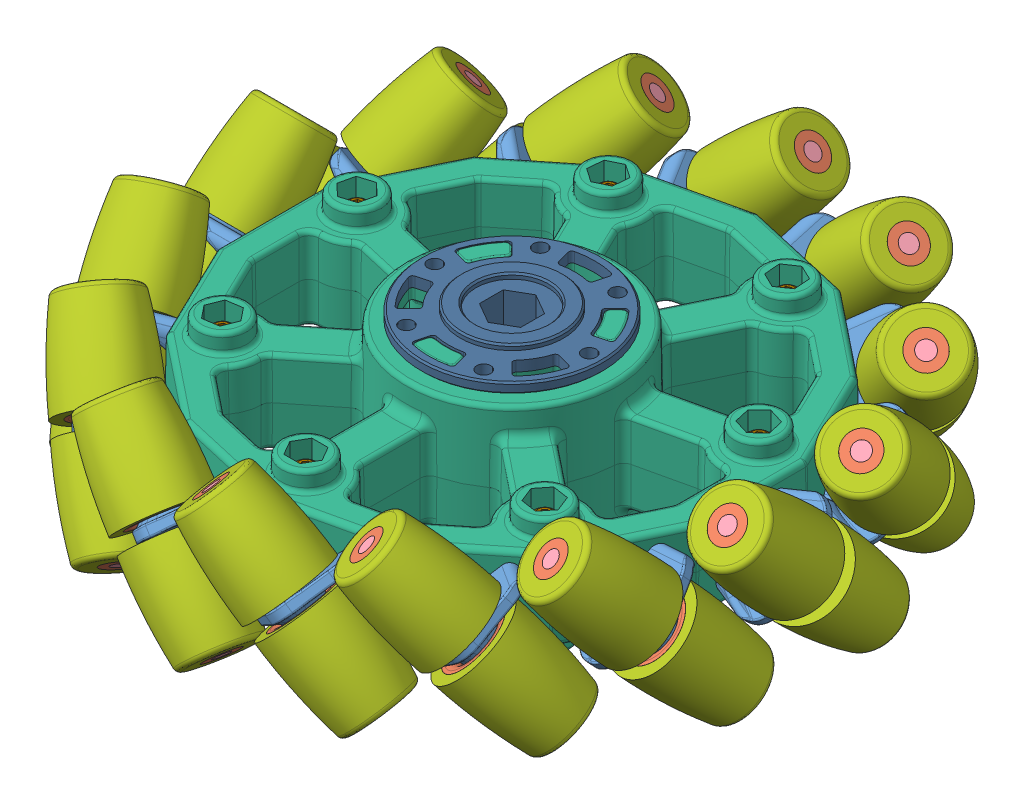
SolidWorks assembly 8in mecanum right vex 217-2587, configuration Default. Lengths in mm.
Overall size (213.38 69.6 218.31).
136 component instances, 11 part files, 6 mates.
Components (placement in the parent):
- 217-2586-002 Rev2-1: 217-2586-002 Rev2 [Default] at (67.5204 0.2406 0.0923) x (0 0 -1) z (1 0 0) size (26.84 25.28 30.09)
- 217-2586-003 Rev2-1: 217-2586-003 Rev2 [Default] at (88.2976 4.2468 4.0985) x (-0.854327 -0.367509 0.367509) z (-0.519737 0.6041 -0.6041) size (19.46 28.57 19.46)
- 217-2586-003 Rev2-2: 217-2586-003 Rev2 [Default] at (88.2976 -3.7657 -3.9139) x (0.717269 -0.492709 0.492709) z (0.696796 0.507186 -0.507186) size (19.46 28.57 19.46)
- 217-2586-005 Rev2-1: 217-2586-005 Rev2 [Default] at (88.2976 6.5692 6.4209) x (0 -0.707107 -0.707107) z (0.707107 -0.5 0.5) size (8.5 8 8)
- 217-2586-005 Rev2-2: 217-2586-005 Rev2 [Default] at (88.2976 -6.088 -6.2363) x (0 -0.707107 -0.707107) z (0.707107 -0.5 0.5) size (8.5 8 8)
- 217-2586-007 Rev1-1: 217-2586-007 Rev1 [Default] at (88.2976 0.2406 0.0923) x (0 -0.707107 -0.707107) z (0.543569 -0.59352 0.59352) size (61.72 5 5)
- 217-2586-008 Rev1-1: 217-2586-008 Rev1 [Default] at (-11.9459 2.5442 -20.6627) x (0.866025 0 -0.5) z (0 -1 0) size (7.33 6.35 31.75)
- 217-2587-001 Rev2-1: 217-2587-001 Rev2 [Default] at (-0.0396 6.3542 -0.0405) x (1 0 0) z (0 -1 0) size (148.4 151.99 28.55)
- 217-2587-001 Rev2-2: 217-2587-001 Rev2 [Default] at (-0.0396 -6.3458 -0.0405) x (-1 0 0) z (0 1 0) size (148.4 151.99 28.55)
- 217-2587-002 Rev2-1: 217-2587-002 Rev2 [Default] at (88.2976 0.6392 0.4909) x (0.779232 -0.443169 0.443169) z (0.626736 0.551 -0.551) size (26.1 28.57 26.1)
- 217-2587-002 Rev2-2: 217-2587-002 Rev2 [Default] at (88.2976 -0.158 -0.3063) x (0.779223 -0.443177 0.443177) z (-0.626747 -0.550994 0.550994) size (26.1 28.57 26.1)
- NUT-832-NYLOCK-1: NUT-832-NYLOCK [Default] at (-49.6859 -13.6521 39.5511) x (0.365341 0 -0.930874) z (-0.930874 0 -0.365341) size (10.2 5.86 8.12)
- SCREW-832-1250-1: SCREW-832-1250 [Default] at (-49.6859 14.914 39.5511) x (0 -1 0) z (0 0 1) size (33.96 7.92 7.92)
- 217-2586-008 Rev1-2: 217-2586-008 Rev1 [Default] at (11.8666 2.5442 -20.6627) x (0.866025 0 0.5) z (0 -1 0) size (7.33 6.35 31.75)
- 217-2586-008 Rev1-3: 217-2586-008 Rev1 [Default] at (23.7729 2.5442 -0.0405) x (0 0 1) z (0 -1 0) size (7.33 6.35 31.75)
- 217-2586-008 Rev1-4: 217-2586-008 Rev1 [Default] at (11.8666 2.5442 20.5817) x (-0.866025 0 0.5) z (0 -1 0) size (7.33 6.35 31.75)
- 217-2586-008 Rev1-5: 217-2586-008 Rev1 [Default] at (-11.9459 2.5442 20.5817) x (-0.866025 0 -0.5) z (0 -1 0) size (7.33 6.35 31.75)
- 217-2586-008 Rev1-6: 217-2586-008 Rev1 [Default] at (-23.8521 2.5442 -0.0405) x (0 0 -1) z (0 -1 0) size (7.33 6.35 31.75)
- NUT-832-NYLOCK-2: NUT-832-NYLOCK [Default] at (-0.0396 -13.6521 63.4595) x (-0.5 0 -0.866025) z (-0.866025 0 0.5) size (10.2 5.86 8.12)
- NUT-832-NYLOCK-3: NUT-832-NYLOCK [Default] at (49.6067 -13.6521 39.5511) x (-0.988831 0 -0.149042) z (-0.149042 0 0.988831) size (10.2 5.86 8.12)
- NUT-832-NYLOCK-4: NUT-832-NYLOCK [Default] at (61.8683 -13.6521 -14.1706) x (-0.733052 0 0.680173) z (0.680173 0 0.733052) size (10.2 5.86 8.12)
- NUT-832-NYLOCK-5: NUT-832-NYLOCK [Default] at (27.512 -13.6521 -57.252) x (0.07473 0 0.997204) z (0.997204 0 -0.07473) size (10.2 5.86 8.12)
- NUT-832-NYLOCK-6: NUT-832-NYLOCK [Default] at (-27.5912 -13.6521 -57.252) x (0.826239 0 0.56332) z (0.56332 0 -0.826239) size (10.2 5.86 8.12)
- NUT-832-NYLOCK-7: NUT-832-NYLOCK [Default] at (-61.9475 -13.6521 -14.1706) x (0.955573 0 -0.294755) z (-0.294755 0 -0.955573) size (10.2 5.86 8.12)
- SCREW-832-1250-2: SCREW-832-1250 [Default] at (-0.0396 14.914 63.4595) x (0 -1 0) z (0.781831 0 0.62349) size (33.96 7.92 7.92)
- SCREW-832-1250-3: SCREW-832-1250 [Default] at (49.6067 14.914 39.5511) x (0 -1 0) z (0.974928 0 -0.222521) size (33.96 7.92 7.92)
- SCREW-832-1250-4: SCREW-832-1250 [Default] at (61.8683 14.914 -14.1706) x (0 -1 0) z (0.433884 0 -0.900969) size (33.96 7.92 7.92)
- SCREW-832-1250-5: SCREW-832-1250 [Default] at (27.512 14.914 -57.252) x (0 -1 0) z (-0.433884 0 -0.900969) size (33.96 7.92 7.92)
- SCREW-832-1250-6: SCREW-832-1250 [Default] at (-27.5912 14.914 -57.252) x (0 -1 0) z (-0.974928 0 -0.222521) size (33.96 7.92 7.92)
- SCREW-832-1250-7: SCREW-832-1250 [Default] at (-61.9475 14.914 -14.1706) x (0 -1 0) z (-0.781831 0 0.62349) size (33.96 7.92 7.92)
- 217-2586-002 Rev2-2: 217-2586-002 Rev2 [Default] at (60.8875 0.2406 -29.234) x (-0.433884 0 -0.900969) z (0.900969 0 -0.433884) size (26.84 25.28 30.09)
- 217-2586-002 Rev2-3: 217-2586-002 Rev2 [Default] at (42.1872 0.2406 -52.7782) x (-0.781831 0 -0.62349) z (0.62349 0 -0.781831) size (26.84 25.28 30.09)
- 217-2586-002 Rev2-4: 217-2586-002 Rev2 [Default] at (15.1234 0.2406 -65.8771) x (-0.974928 0 -0.222521) z (0.222521 0 -0.974928) size (26.84 25.28 30.09)
- 217-2586-002 Rev2-5: 217-2586-002 Rev2 [Default] at (-14.9437 0.2406 -65.9362) x (-0.974928 0 0.222521) z (-0.222521 0 -0.974928) size (26.84 25.28 30.09)
- 217-2586-002 Rev2-6: 217-2586-002 Rev2 [Default] at (-42.0588 0.2406 -52.9438) x (-0.781831 0 0.62349) z (-0.62349 0 -0.781831) size (26.84 25.28 30.09)
- 217-2586-002 Rev2-7: 217-2586-002 Rev2 [Default] at (-60.8515 0.2406 -29.4733) x (-0.433884 0 0.900969) z (-0.900969 0 -0.433884) size (26.84 25.28 30.09)
- 217-2586-002 Rev2-8: 217-2586-002 Rev2 [Default] at (-67.5996 0.2406 -0.1733) x (0 0 1) z (-1 0 0) size (26.84 25.28 30.09)
- 217-2586-002 Rev2-9: 217-2586-002 Rev2 [Default] at (-60.9667 0.2406 29.1531) x (0.433884 0 0.900969) z (-0.900969 0 0.433884) size (26.84 25.28 30.09)
- 217-2586-002 Rev2-10: 217-2586-002 Rev2 [Default] at (-42.2664 0.2406 52.6973) x (0.781831 0 0.62349) z (-0.62349 0 0.781831) size (26.84 25.28 30.09)
- 217-2586-002 Rev2-11: 217-2586-002 Rev2 [Default] at (-15.2026 0.2406 65.7961) x (0.974928 0 0.222521) z (-0.222521 0 0.974928) size (26.84 25.28 30.09)
- 217-2586-002 Rev2-12: 217-2586-002 Rev2 [Default] at (14.8644 0.2406 65.8552) x (0.974928 0 -0.222521) z (0.222521 0 0.974928) size (26.84 25.28 30.09)
- 217-2586-002 Rev2-13: 217-2586-002 Rev2 [Default] at (41.9795 0.2406 52.8628) x (0.781831 0 -0.62349) z (0.62349 0 0.781831) size (26.84 25.28 30.09)
- 217-2586-002 Rev2-14: 217-2586-002 Rev2 [Default] at (60.7722 0.2406 29.3923) x (0.433884 0 -0.900969) z (0.900969 0 0.433884) size (26.84 25.28 30.09)
- 217-2586-003 Rev2-3: 217-2586-003 Rev2 [Default] at (81.3453 4.2468 -34.6394) x (-0.610265 -0.367509 0.701793) z (-0.730376 0.6041 -0.31877) size (19.46 28.57 19.46)
- 217-2586-003 Rev2-4: 217-2586-003 Rev2 [Default] at (58.2737 4.2468 -66.5247) x (-0.245334 -0.367509 0.897078) z (-0.796355 0.6041 0.029696) size (19.46 28.57 19.46)
- 217-2586-003 Rev2-5: 217-2586-003 Rev2 [Default] at (23.6525 4.2468 -85.2419) x (0.16819 -0.367509 0.914685) z (-0.704606 0.6041 0.372281) size (19.46 28.57 19.46)
- 217-2586-003 Rev2-6: 217-2586-003 Rev2 [Default] at (-15.6612 4.2468 -87.0839) x (0.548401 -0.367509 0.751128) z (-0.473302 0.6041 0.641131) size (19.46 28.57 19.46)
- 217-2586-003 Rev2-7: 217-2586-003 Rev2 [Default] at (-51.8809 4.2468 -71.6859) x (0.819994 -0.367509 0.438801) z (-0.148254 0.6041 0.782997) size (19.46 28.57 19.46)
- 217-2586-003 Rev2-8: 217-2586-003 Rev2 [Default] at (-77.8328 4.2468 -42.0977) x (0.929178 -0.367509 0.039564) z (0.206157 0.6041 0.769781) size (19.46 28.57 19.46)
- 217-2586-003 Rev2-9: 217-2586-003 Rev2 [Default] at (-88.3768 4.2468 -4.1795) x (0.854327 -0.367509 -0.367509) z (0.519737 0.6041 0.6041) size (19.46 28.57 19.46)
- 217-2586-003 Rev2-10: 217-2586-003 Rev2 [Default] at (-81.4245 4.2468 34.5585) x (0.610265 -0.367509 -0.701793) z (0.730376 0.6041 0.31877) size (19.46 28.57 19.46)
- 217-2586-003 Rev2-11: 217-2586-003 Rev2 [Default] at (-58.353 4.2468 66.4437) x (0.245334 -0.367509 -0.897078) z (0.796355 0.6041 -0.029696) size (19.46 28.57 19.46)
- 217-2586-003 Rev2-12: 217-2586-003 Rev2 [Default] at (-23.7317 4.2468 85.1609) x (-0.16819 -0.367509 -0.914685) z (0.704606 0.6041 -0.372281) size (19.46 28.57 19.46)
- 217-2586-003 Rev2-13: 217-2586-003 Rev2 [Default] at (15.582 4.2468 87.0029) x (-0.548401 -0.367509 -0.751128) z (0.473302 0.6041 -0.641131) size (19.46 28.57 19.46)
- 217-2586-003 Rev2-14: 217-2586-003 Rev2 [Default] at (51.8017 4.2468 71.605) x (-0.819994 -0.367509 -0.438801) z (0.148254 0.6041 -0.782997) size (19.46 28.57 19.46)
- 217-2586-003 Rev2-15: 217-2586-003 Rev2 [Default] at (77.7536 4.2468 42.0167) x (-0.929178 -0.367509 -0.039564) z (-0.206157 0.6041 -0.769781) size (19.46 28.57 19.46)
- 217-2586-003 Rev2-16: 217-2586-003 Rev2 [Default] at (77.8688 -3.7657 -41.8584) x (0.860016 -0.492709 0.132704) z (0.407732 0.507186 -0.759287) size (19.46 28.57 19.46)
- 217-2586-003 Rev2-17: 217-2586-003 Rev2 [Default] at (52.0094 -3.7657 -71.5203) x (0.832426 -0.492709 -0.253585) z (0.037911 0.507186 -0.861002) size (19.46 28.57 19.46)
- 217-2586-003 Rev2-18: 217-2586-003 Rev2 [Default] at (15.8409 -3.7657 -87.0248) x (0.639963 -0.492709 -0.589648) z (-0.339418 0.507186 -0.792185) size (19.46 28.57 19.46)
- 217-2586-003 Rev2-19: 217-2586-003 Rev2 [Default] at (-23.4728 -3.7657 -85.301) x (0.320749 -0.492709 -0.808924) z (-0.649521 0.507186 -0.566466) size (19.46 28.57 19.46)
- 217-2586-003 Rev2-20: 217-2586-003 Rev2 [Default] at (-58.1453 -3.7657 -66.6902) x (-0.061995 -0.492709 -0.867983) z (-0.830979 0.507186 -0.228552) size (19.46 28.57 19.46)
- 217-2586-003 Rev2-21: 217-2586-003 Rev2 [Default] at (-81.3093 -3.7657 -34.8787) x (-0.432459 -0.492709 -0.755127) z (-0.847851 0.507186 0.15463) size (19.46 28.57 19.46)
- 217-2586-003 Rev2-22: 217-2586-003 Rev2 [Default] at (-88.3768 -3.7657 3.833) x (-0.717269 -0.492709 -0.492709) z (-0.696796 0.507186 0.507186) size (19.46 28.57 19.46)
- 217-2586-003 Rev2-23: 217-2586-003 Rev2 [Default] at (-77.9481 -3.7657 41.7774) x (-0.860016 -0.492709 -0.132704) z (-0.407732 0.507186 0.759287) size (19.46 28.57 19.46)
- 217-2586-003 Rev2-24: 217-2586-003 Rev2 [Default] at (-52.0886 -3.7657 71.4394) x (-0.832426 -0.492709 0.253585) z (-0.037911 0.507186 0.861002) size (19.46 28.57 19.46)
- 217-2586-003 Rev2-25: 217-2586-003 Rev2 [Default] at (-15.9202 -3.7657 86.9438) x (-0.639963 -0.492709 0.589648) z (0.339418 0.507186 0.792185) size (19.46 28.57 19.46)
- 217-2586-003 Rev2-26: 217-2586-003 Rev2 [Default] at (23.3936 -3.7657 85.22) x (-0.320749 -0.492709 0.808924) z (0.649521 0.507186 0.566466) size (19.46 28.57 19.46)
- 217-2586-003 Rev2-27: 217-2586-003 Rev2 [Default] at (58.0661 -3.7657 66.6093) x (0.061995 -0.492709 0.867983) z (0.830979 0.507186 0.228552) size (19.46 28.57 19.46)
- 217-2586-003 Rev2-28: 217-2586-003 Rev2 [Default] at (81.2301 -3.7657 34.7977) x (0.432459 -0.492709 0.755127) z (0.847851 0.507186 -0.15463) size (19.46 28.57 19.46)
- 217-2586-005 Rev2-3: 217-2586-005 Rev2 [Default] at (82.3529 6.5692 -32.547) x (-0.306802 -0.707107 -0.637081) z (0.854023 -0.5 0.143682) size (8.5 8 8)
- 217-2586-005 Rev2-4: 217-2586-005 Rev2 [Default] at (60.0895 6.5692 -65.0767) x (-0.552838 -0.707107 -0.440874) z (0.83179 -0.5 -0.241093) size (8.5 8 8)
- 217-2586-005 Rev2-5: 217-2586-005 Rev2 [Default] at (25.9167 6.5692 -84.7251) x (-0.689378 -0.707107 -0.157346) z (0.64481 -0.5 -0.578118) size (8.5 8 8)
- 217-2586-005 Rev2-6: 217-2586-005 Rev2 [Default] at (-13.3971 6.5692 -87.6007) x (-0.689378 -0.707107 0.157346) z (0.330118 -0.5 -0.800639) size (8.5 8 8)
- 217-2586-005 Rev2-7: 217-2586-005 Rev2 [Default] at (-50.0652 6.5692 -73.1339) x (-0.552838 -0.707107 0.440874) z (-0.049958 -0.5 -0.864583) size (8.5 8 8)
- 217-2586-005 Rev2-8: 217-2586-005 Rev2 [Default] at (-76.8252 6.5692 -44.1901) x (-0.306802 -0.707107 0.637081) z (-0.420139 -0.5 -0.757287) size (8.5 8 8)
- 217-2586-005 Rev2-9: 217-2586-005 Rev2 [Default] at (-88.3768 6.5692 -6.5019) x (0 -0.707107 0.707107) z (-0.707107 -0.5 -0.5) size (8.5 8 8)
- 217-2586-005 Rev2-10: 217-2586-005 Rev2 [Default] at (-82.4322 6.5692 32.4661) x (0.306802 -0.707107 0.637081) z (-0.854023 -0.5 -0.143682) size (8.5 8 8)
- 217-2586-005 Rev2-11: 217-2586-005 Rev2 [Default] at (-60.1687 6.5692 64.9957) x (0.552838 -0.707107 0.440874) z (-0.83179 -0.5 0.241093) size (8.5 8 8)
- 217-2586-005 Rev2-12: 217-2586-005 Rev2 [Default] at (-25.9959 6.5692 84.6441) x (0.689378 -0.707107 0.157346) z (-0.64481 -0.5 0.578118) size (8.5 8 8)
- 217-2586-005 Rev2-13: 217-2586-005 Rev2 [Default] at (13.3179 6.5692 87.5197) x (0.689378 -0.707107 -0.157346) z (-0.330118 -0.5 0.800639) size (8.5 8 8)
- 217-2586-005 Rev2-14: 217-2586-005 Rev2 [Default] at (49.986 6.5692 73.0529) x (0.552838 -0.707107 -0.440874) z (0.049958 -0.5 0.864583) size (8.5 8 8)
- 217-2586-005 Rev2-15: 217-2586-005 Rev2 [Default] at (76.746 6.5692 44.1091) x (0.306802 -0.707107 -0.637081) z (0.420139 -0.5 0.757287) size (8.5 8 8)
- 217-2586-005 Rev2-16: 217-2586-005 Rev2 [Default] at (76.8612 -6.088 -43.9508) x (-0.306802 -0.707107 -0.637081) z (0.854023 -0.5 0.143682) size (8.5 8 8)
- 217-2586-005 Rev2-17: 217-2586-005 Rev2 [Default] at (50.1936 -6.088 -72.9683) x (-0.552838 -0.707107 -0.440874) z (0.83179 -0.5 -0.241093) size (8.5 8 8)
- 217-2586-005 Rev2-18: 217-2586-005 Rev2 [Default] at (13.5768 -6.088 -87.5416) x (-0.689378 -0.707107 -0.157346) z (0.64481 -0.5 -0.578118) size (8.5 8 8)
- 217-2586-005 Rev2-19: 217-2586-005 Rev2 [Default] at (-25.737 -6.088 -84.7842) x (-0.689378 -0.707107 0.157346) z (0.330118 -0.5 -0.800639) size (8.5 8 8)
- 217-2586-005 Rev2-20: 217-2586-005 Rev2 [Default] at (-59.961 -6.088 -65.2423) x (-0.552838 -0.707107 0.440874) z (-0.049958 -0.5 -0.864583) size (8.5 8 8)
- 217-2586-005 Rev2-21: 217-2586-005 Rev2 [Default] at (-82.3169 -6.088 -32.7863) x (-0.306802 -0.707107 0.637081) z (-0.420139 -0.5 -0.757287) size (8.5 8 8)
- 217-2586-005 Rev2-22: 217-2586-005 Rev2 [Default] at (-88.3768 -6.088 6.1553) x (0 -0.707107 0.707107) z (-0.707107 -0.5 -0.5) size (8.5 8 8)
- 217-2586-005 Rev2-23: 217-2586-005 Rev2 [Default] at (-76.9404 -6.088 43.8698) x (0.306802 -0.707107 0.637081) z (-0.854023 -0.5 -0.143682) size (8.5 8 8)
- 217-2586-005 Rev2-24: 217-2586-005 Rev2 [Default] at (-50.2729 -6.088 72.8873) x (0.552838 -0.707107 0.440874) z (-0.83179 -0.5 0.241093) size (8.5 8 8)
- 217-2586-005 Rev2-25: 217-2586-005 Rev2 [Default] at (-13.656 -6.088 87.4606) x (0.689378 -0.707107 0.157346) z (-0.64481 -0.5 0.578118) size (8.5 8 8)
- 217-2586-005 Rev2-26: 217-2586-005 Rev2 [Default] at (25.6577 -6.088 84.7032) x (0.689378 -0.707107 -0.157346) z (-0.330118 -0.5 0.800639) size (8.5 8 8)
- 217-2586-005 Rev2-27: 217-2586-005 Rev2 [Default] at (59.8818 -6.088 65.1613) x (0.552838 -0.707107 -0.440874) z (0.049958 -0.5 0.864583) size (8.5 8 8)
- 217-2586-005 Rev2-28: 217-2586-005 Rev2 [Default] at (82.2377 -6.088 32.7054) x (0.306802 -0.707107 -0.637081) z (0.420139 -0.5 0.757287) size (8.5 8 8)
- 217-2586-007 Rev1-2: 217-2586-007 Rev1 [Default] at (79.6071 0.2406 -38.2489) x (-0.306802 -0.707107 -0.637081) z (0.747258 -0.59352 0.298897) size (61.72 5 5)
- 217-2586-007 Rev1-3: 217-2586-007 Rev1 [Default] at (55.1416 0.2406 -69.0225) x (-0.552838 -0.707107 -0.440874) z (0.802943 -0.59352 -0.054926) size (61.72 5 5)
- 217-2586-007 Rev1-4: 217-2586-007 Rev1 [Default] at (19.7467 0.2406 -86.1333) x (-0.689378 -0.707107 -0.157346) z (0.699595 -0.59352 -0.39787) size (61.72 5 5)
- 217-2586-007 Rev1-5: 217-2586-007 Rev1 [Default] at (-19.567 0.2406 -86.1924) x (-0.689378 -0.707107 0.157346) z (0.457684 -0.59352 -0.662011) size (61.72 5 5)
- 217-2586-007 Rev1-6: 217-2586-007 Rev1 [Default] at (-55.0131 0.2406 -69.1881) x (-0.552838 -0.707107 0.440874) z (0.125123 -0.59352 -0.795033) size (61.72 5 5)
- 217-2586-007 Rev1-7: 217-2586-007 Rev1 [Default] at (-79.5711 0.2406 -38.4882) x (-0.306802 -0.707107 0.637081) z (-0.23222 -0.59352 -0.770589) size (61.72 5 5)
- 217-2586-007 Rev1-8: 217-2586-007 Rev1 [Default] at (-88.3768 0.2406 -0.1733) x (0 -0.707107 0.707107) z (-0.543569 -0.59352 -0.59352) size (61.72 5 5)
- 217-2586-007 Rev1-9: 217-2586-007 Rev1 [Default] at (-79.6863 0.2406 38.168) x (0.306802 -0.707107 0.637081) z (-0.747258 -0.59352 -0.298897) size (61.72 5 5)
- 217-2586-007 Rev1-10: 217-2586-007 Rev1 [Default] at (-55.2208 0.2406 68.9415) x (0.552838 -0.707107 0.440874) z (-0.802943 -0.59352 0.054926) size (61.72 5 5)
- 217-2586-007 Rev1-11: 217-2586-007 Rev1 [Default] at (-19.8259 0.2406 86.0524) x (0.689378 -0.707107 0.157346) z (-0.699595 -0.59352 0.39787) size (61.72 5 5)
- 217-2586-007 Rev1-12: 217-2586-007 Rev1 [Default] at (19.4878 0.2406 86.1115) x (0.689378 -0.707107 -0.157346) z (-0.457684 -0.59352 0.662011) size (61.72 5 5)
- 217-2586-007 Rev1-13: 217-2586-007 Rev1 [Default] at (54.9339 0.2406 69.1071) x (0.552838 -0.707107 -0.440874) z (-0.125123 -0.59352 0.795033) size (61.72 5 5)
- 217-2586-007 Rev1-14: 217-2586-007 Rev1 [Default] at (79.4918 0.2406 38.4072) x (0.306802 -0.707107 -0.637081) z (0.23222 -0.59352 0.770589) size (61.72 5 5)
- 217-2587-002 Rev2-3: 217-2587-002 Rev2 [Default] at (79.4341 -0.158 -38.608) x (0.894343 -0.443177 0.061196) z (-0.325612 -0.550994 0.768364) size (26.1 28.57 26.1)
- 217-2587-002 Rev2-4: 217-2587-002 Rev2 [Default] at (54.8299 -0.158 -69.271) x (0.832327 -0.443177 -0.332905) z (0.040014 -0.550994 0.833549) size (26.1 28.57 26.1)
- 217-2587-002 Rev2-5: 217-2587-002 Rev2 [Default] at (19.3581 -0.158 -86.222) x (0.605459 -0.443177 -0.66107) z (0.397715 -0.550994 0.73364) size (26.1 28.57 26.1)
- 217-2587-002 Rev2-6: 217-2587-002 Rev2 [Default] at (-19.9556 -0.158 -86.1037) x (0.258672 -0.443177 -0.858303) z (0.676644 -0.550994 0.488425) size (26.1 28.57 26.1)
- 217-2587-002 Rev2-7: 217-2587-002 Rev2 [Default] at (-55.3248 -0.158 -68.9396) x (-0.139348 -0.443177 -0.885537) z (0.821555 -0.550994 0.146471) size (26.1 28.57 26.1)
- 217-2587-002 Rev2-8: 217-2587-002 Rev2 [Default] at (-79.744 -0.158 -38.1291) x (-0.509769 -0.443177 -0.737381) z (0.803746 -0.550994 -0.224493) size (26.1 28.57 26.1)
- 217-2587-002 Rev2-9: 217-2587-002 Rev2 [Default] at (-88.3768 -0.158 0.2253) x (-0.779223 -0.443177 -0.443177) z (0.626747 -0.550994 -0.550994) size (26.1 28.57 26.1)
- 217-2587-002 Rev2-10: 217-2587-002 Rev2 [Default] at (-79.5134 -0.158 38.5271) x (-0.894343 -0.443177 -0.061196) z (0.325612 -0.550994 -0.768364) size (26.1 28.57 26.1)
- 217-2587-002 Rev2-11: 217-2587-002 Rev2 [Default] at (-54.9092 -0.158 69.19) x (-0.832327 -0.443177 0.332905) z (-0.040014 -0.550994 -0.833549) size (26.1 28.57 26.1)
- 217-2587-002 Rev2-12: 217-2587-002 Rev2 [Default] at (-19.4374 -0.158 86.1411) x (-0.605459 -0.443177 0.66107) z (-0.397715 -0.550994 -0.73364) size (26.1 28.57 26.1)
- 217-2587-002 Rev2-13: 217-2587-002 Rev2 [Default] at (19.8764 -0.158 86.0228) x (-0.258672 -0.443177 0.858303) z (-0.676644 -0.550994 -0.488425) size (26.1 28.57 26.1)
- 217-2587-002 Rev2-14: 217-2587-002 Rev2 [Default] at (55.2455 -0.158 68.8586) x (0.139348 -0.443177 0.885537) z (-0.821555 -0.550994 -0.146471) size (26.1 28.57 26.1)
- 217-2587-002 Rev2-15: 217-2587-002 Rev2 [Default] at (79.6648 -0.158 38.0481) x (0.509769 -0.443177 0.737381) z (-0.803746 -0.550994 0.224493) size (26.1 28.57 26.1)
- 217-2587-002 Rev2-16: 217-2587-002 Rev2 [Default] at (79.78 0.6392 -37.8898) x (0.894347 -0.443169 0.061186) z (0.3256 0.551 -0.768364) size (26.1 28.57 26.1)
- 217-2587-002 Rev2-17: 217-2587-002 Rev2 [Default] at (55.4532 0.6392 -68.774) x (0.832327 -0.443169 -0.332916) z (-0.040026 0.551 -0.833545) size (26.1 28.57 26.1)
- 217-2587-002 Rev2-18: 217-2587-002 Rev2 [Default] at (20.1353 0.6392 -86.0446) x (0.605453 -0.443169 -0.66108) z (-0.397723 0.551 -0.733631) size (26.1 28.57 26.1)
- 217-2587-002 Rev2-19: 217-2587-002 Rev2 [Default] at (-19.1784 0.6392 -86.2811) x (0.258663 -0.443169 -0.858309) z (-0.676647 0.551 -0.488413) size (26.1 28.57 26.1)
- 217-2587-002 Rev2-20: 217-2587-002 Rev2 [Default] at (-54.7015 0.6392 -69.4366) x (-0.139359 -0.443169 -0.885539) z (-0.821553 0.551 -0.146459) size (26.1 28.57 26.1)
- 217-2587-002 Rev2-21: 217-2587-002 Rev2 [Default] at (-79.3981 0.6392 -38.8473) x (-0.509779 -0.443169 -0.737378) z (-0.80374 0.551 0.224503) size (26.1 28.57 26.1)
- 217-2587-002 Rev2-22: 217-2587-002 Rev2 [Default] at (-88.3768 0.6392 -0.5718) x (-0.779232 -0.443169 -0.443169) z (-0.626736 0.551 0.551) size (26.1 28.57 26.1)
- 217-2587-002 Rev2-23: 217-2587-002 Rev2 [Default] at (-79.8592 0.6392 37.8088) x (-0.894347 -0.443169 -0.061186) z (-0.3256 0.551 0.768364) size (26.1 28.57 26.1)
- 217-2587-002 Rev2-24: 217-2587-002 Rev2 [Default] at (-55.5324 0.6392 68.693) x (-0.832327 -0.443169 0.332916) z (0.040026 0.551 0.833545) size (26.1 28.57 26.1)
- 217-2587-002 Rev2-25: 217-2587-002 Rev2 [Default] at (-20.2145 0.6392 85.9637) x (-0.605453 -0.443169 0.66108) z (0.397723 0.551 0.733631) size (26.1 28.57 26.1)
- 217-2587-002 Rev2-26: 217-2587-002 Rev2 [Default] at (19.0992 0.6392 86.2002) x (-0.258663 -0.443169 0.858309) z (0.676647 0.551 0.488413) size (26.1 28.57 26.1)
- 217-2587-002 Rev2-27: 217-2587-002 Rev2 [Default] at (54.6223 0.6392 69.3556) x (0.139359 -0.443169 0.885539) z (0.821553 0.551 0.146459) size (26.1 28.57 26.1)
- 217-2587-002 Rev2-28: 217-2587-002 Rev2 [Default] at (79.3189 0.6392 38.7663) x (0.509779 -0.443169 0.737378) z (0.80374 0.551 -0.224503) size (26.1 28.57 26.1)
- Versahub 0.5in hex-1: Versahub 0.5in hex [Default] at (-0.0396 12.0692 -0.0405) x (0 1 0) z (0.866025 0 0.5) size (14.3 55.88 55.88)
- 0.5in hex bearing-1: 0.5in hex bearing [Default] at (-0.0396 -15.2358 -0.0405) x (0.866025 0 -0.5) z (0 -1 0) size (31.12 31.12 7.94)
Mates (geometry in assembly coordinates):
- Concentric1: concentric aligned: cylinder of 217-2587-001 Rev2-1 through (-0.0396 21.5942 -0.0405) axis (0 -1 0) radius 14.3; cylinder of Versahub 0.5in hex-1 through (-0.0396 12.0692 -0.0405) axis (0 -1 0) radius 14.295
- Parallel1: parallel anti-aligned: plane of 217-2587-001 Rev2-1 through (-6.6395 24.7692 24.5906) normal (-0.965926 0 -0.258819); plane of Versahub 0.5in hex-1 through (-6.6878 21.5942 24.5776) normal (0.965926 0 0.258819)
- Coincident1: coincident anti-aligned: plane of 217-2587-001 Rev2-1 through (-0.0396 21.5942 -0.0405) normal (0 1 0); plane of Versahub 0.5in hex-1 through (-7.1871 21.5942 12.3393) normal (0 -1 0)
- Coincident2: coincident anti-aligned: plane of 217-2587-001 Rev2-2 through (-0.0396 -21.5858 -0.0405) normal (0 -1 0); plane of 0.5in hex bearing-1 through (-0.0396 -21.5858 -0.0405) normal (0 1 0)
- Concentric3: concentric aligned: cylinder of 217-2587-001 Rev2-2 through (-0.0396 -21.5858 -0.0405) axis (0 1 0) radius 14.3; cylinder of 0.5in hex bearing-1 through (-0.0396 -21.5858 -0.0405) axis (0 1 0) radius 14.2748
- Parallel3: parallel aligned: plane of Versahub 0.5in hex-1 through (-0.0396 12.0692 7.3065) normal (-0.5 0 -0.866025); plane of 0.5in hex bearing-1 through (-0.0396 -23.1733 7.2919) normal (-0.5 0 -0.866025)
